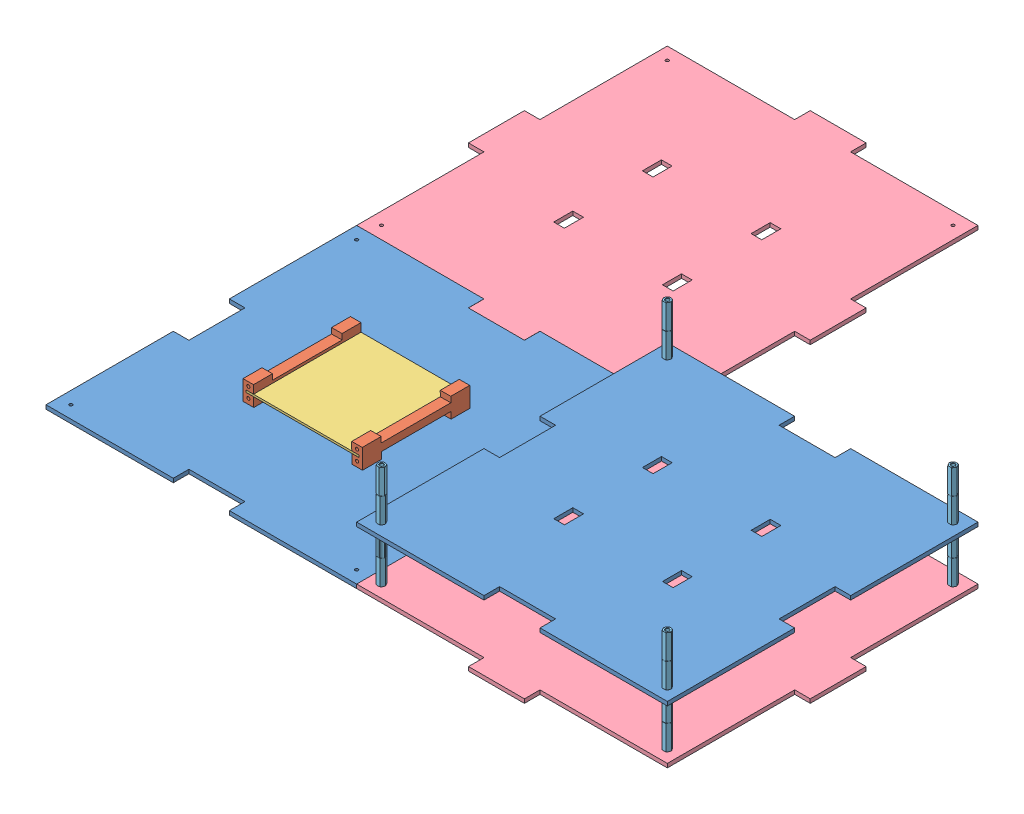
SolidWorks assembly Assem1, configuration Default. Lengths in mm.
Overall size (524.95 91.39 524.9).
25 component instances, 5 part files, 0 mates.
Components (placement in the parent):
- AssemblyExample-1: AssemblyExample [Default] at (-234.1729 -3.2077 158.115) size (524.95 91.39 524.9)
  - BOTTOM_JIGSAW_1-1: BOTTOM_JIGSAW_1 [Default] at (-30.048 7.9481 9.3776) size (250 3.17 250)
  - Modified_PCB_Shelf-1: Modified_PCB_Shelf [Default] at (-78.0795 11.9144 52.7276) x (0.999969 0.007891 0) z (0 0 1) size (8.5 19 86.5)
  - Modified_PCB_Shelf-2: Modified_PCB_Shelf [Default] at (17.9203 11.9815 -33.7724) x (-0.999969 -0.007883 0) z (0 0 -1) size (8.5 19 86.5)
  - FAKE_PCB-1: FAKE_PCB [Default] at (-75.6449 18.5839 52.7276) x (1 0.000303 0) z (0 0 1) size (91 1.7 86.5)
  - BOTTOM_JIGSAW_2-1: BOTTOM_JIGSAW_2 [Default] at (219.902 11.1231 9.3276) x (1 0 0) z (0 0 -1) size (275 3.17 275)
  - BOTTOM_JIGSAW_1-2: BOTTOM_JIGSAW_1 [Default] at (219.902 51.1231 9.3276) size (250 3.17 250)
  - BOTTOM_JIGSAW_2-2: BOTTOM_JIGSAW_2 [Default] at (-30.048 7.9481 -240.5724) size (275 3.17 275)
  - hexagonal_spacer_MF_M3_H20_HEX5.5_FTD8_MTL8.step-2: hexagonal_spacer_MF_M3_H20_HEX5.5_FTD8_MTL8.step [Default] at (104.902 31.1231 124.3276) x (0.970554 0 0.240883) z (0 1 0) size (6.36 5.51 28.21)
  - hexagonal_spacer_MF_M3_H20_HEX5.5_FTD8_MTL8.step-7: hexagonal_spacer_MF_M3_H20_HEX5.5_FTD8_MTL8.step [Default] at (99.902 31.1231 -110.6724) x (0.970554 0 0.240883) z (0 1 0) size (6.36 5.51 28.21)
  - hexagonal_spacer_MF_M3_H20_HEX5.5_FTD8_MTL8.step-8: hexagonal_spacer_MF_M3_H20_HEX5.5_FTD8_MTL8.step [Default] at (99.902 11.1231 -110.6724) x (1 0 0) z (0 1 0) size (6.36 5.51 28.21)
  - hexagonal_spacer_MF_M3_H20_HEX5.5_FTD8_MTL8.step-12: hexagonal_spacer_MF_M3_H20_HEX5.5_FTD8_MTL8.step [Default] at (104.902 54.2981 -105.6724) x (1 0 0) z (0 1 0) size (6.36 5.51 28.21)
  - hexagonal_spacer_MF_M3_H20_HEX5.5_FTD8_MTL8.step-13: hexagonal_spacer_MF_M3_H20_HEX5.5_FTD8_MTL8.step [Default] at (104.902 54.2981 124.3276) x (1 0 0) z (0 1 0) size (6.36 5.51 28.21)
  - hexagonal_spacer_MF_M3_H20_HEX5.5_FTD8_MTL8.step-14: hexagonal_spacer_MF_M3_H20_HEX5.5_FTD8_MTL8.step [Default] at (334.902 54.2981 -105.6724) x (1 0 0) z (0 1 0) size (6.36 5.51 28.21)
  - hexagonal_spacer_MF_M3_H20_HEX5.5_FTD8_MTL8.step-15: hexagonal_spacer_MF_M3_H20_HEX5.5_FTD8_MTL8.step [Default] at (104.902 74.2981 124.3276) x (-0.34676 0 -0.937954) z (0 1 0) size (6.36 5.51 28.21)
  - hexagonal_spacer_MF_M3_H20_HEX5.5_FTD8_MTL8.step-17: hexagonal_spacer_MF_M3_H20_HEX5.5_FTD8_MTL8.step [Default] at (334.902 74.2981 -105.6724) x (1 0 0) z (0 1 0) size (6.36 5.51 28.21)
  - hexagonal_spacer_MF_M3_H20_HEX5.5_FTD8_MTL8.step-18: hexagonal_spacer_MF_M3_H20_HEX5.5_FTD8_MTL8.step [Default] at (104.902 74.2981 -105.6724) x (0.999827 0 -0.018614) z (0 1 0) size (6.36 5.51 28.21)
  - hexagonal_spacer_MF_M3_H20_HEX5.5_FTD8_MTL8.step-19: hexagonal_spacer_MF_M3_H20_HEX5.5_FTD8_MTL8.step [Default] at (334.902 31.1231 124.3276) x (1 0 0) z (0 1 0) size (6.36 5.51 28.21)
  - hexagonal_spacer_MF_M3_H20_HEX5.5_FTD8_MTL8.step-20: hexagonal_spacer_MF_M3_H20_HEX5.5_FTD8_MTL8.step [Default] at (334.902 11.1231 124.3276) x (1 0 0) z (0 1 0) size (6.36 5.51 28.21)
  - hexagonal_spacer_MF_M3_H20_HEX5.5_FTD8_MTL8.step-21: hexagonal_spacer_MF_M3_H20_HEX5.5_FTD8_MTL8.step [Default] at (334.902 74.2981 124.3276) x (1 0 0) z (0 1 0) size (6.36 5.51 28.21)
  - hexagonal_spacer_MF_M3_H20_HEX5.5_FTD8_MTL8.step-22: hexagonal_spacer_MF_M3_H20_HEX5.5_FTD8_MTL8.step [Default] at (334.902 54.2981 124.3276) x (1 0 0) z (0 1 0) size (6.36 5.51 28.21)
  - hexagonal_spacer_MF_M3_H20_HEX5.5_FTD8_MTL8.step-23: hexagonal_spacer_MF_M3_H20_HEX5.5_FTD8_MTL8.step [Default] at (334.902 31.1231 -105.6724) x (1 0 0) z (0 1 0) size (6.36 5.51 28.21)
  - hexagonal_spacer_MF_M3_H20_HEX5.5_FTD8_MTL8.step-24: hexagonal_spacer_MF_M3_H20_HEX5.5_FTD8_MTL8.step [Default] at (334.902 11.1231 -105.6724) x (1 0 0) z (0 1 0) size (6.36 5.51 28.21)
  - hexagonal_spacer_MF_M3_H20_HEX5.5_FTD8_MTL8.step-25: hexagonal_spacer_MF_M3_H20_HEX5.5_FTD8_MTL8.step [Default] at (104.902 31.1231 124.3276) x (1 0 0) z (0 1 0) size (6.36 5.51 28.21)
  - hexagonal_spacer_MF_M3_H20_HEX5.5_FTD8_MTL8.step-26: hexagonal_spacer_MF_M3_H20_HEX5.5_FTD8_MTL8.step [Default] at (104.902 11.1231 124.3276) x (1 0 0) z (0 1 0) size (6.36 5.51 28.21)
